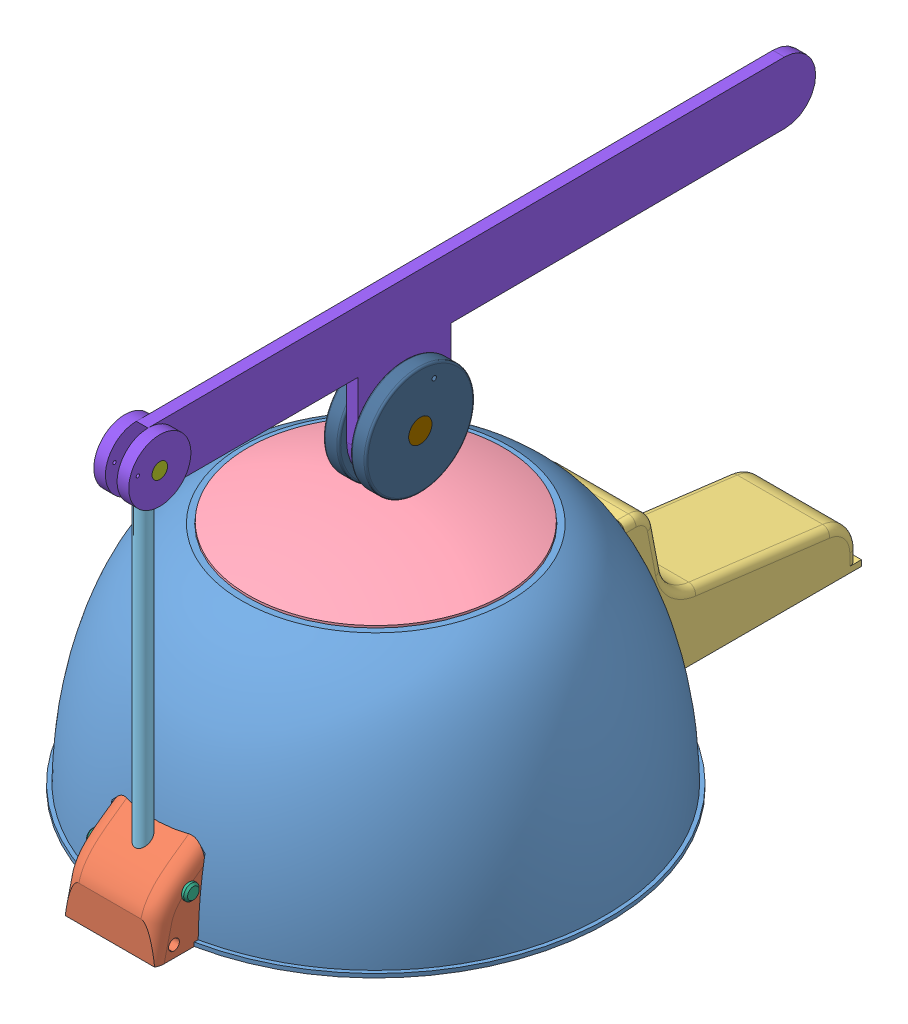
SolidWorks assembly 51  Coupe de l'assemblage, configuration Défaut. Lengths in mm.
Overall size (120 112.85 181.55).
12 component instances, 10 part files, 20 mates.
Components (placement in the parent):
- 1  Coupelle extérieure-1: 1  Coupelle extérieure [Défaut] at (42.4148 -15.5563 120.5) size (120 60 121.39)
- 2  Fixation arrière-1: 2  Fixation arrière [Défaut] at (-29.5852 -15.5563 177) x (0 0 -1) z (1 0 0) size (14.24 23.41 24.92)
- 3  Fixation avant-1: 3  Fixation avant [Défaut] at (-30.4444 -15.7632 69.5) x (0 0 -1) z (1 0 0) size (61 39.79 26)
- 4  Piston-1: 4  Piston [Défaut] at (-17.5852 33.9447 120.5) x (-0.981005 0 0.193982) z (-0.193982 0 -0.981005) size (65.8 16 65.8)
- 51  Assemblage-1: 51  Assemblage [Défaut] at (122.4148 13.8625 229.7525) x (0 0 1) z (-1 0 0) size (4 94 26)
  - 5  Tige de rappel-1: 5  Tige de rappel [Défaut] at (-51.2525 -16.4187 140) size (4 90 4)
  - 6  Tige transversale Bas-1: 6  Tige transversale Bas [Défaut] at (-49.2525 -16.4187 127) size (4 4 26)
  - 8 Tige transversale Haut-1: 8 Tige transversale Haut [Défaut] at (-49.2525 73.5813 144.6486) x (0 0 -1) z (1 0 0) size (9 4 4)
- 7  Levier-1: 7  Levier [Défaut] at (-19.2338 80.3433 -3.5369) x (0 0.004888 -0.999988) z (1 0 0) size (180 44 9)
- 10  Axe de roulettes-1: 10  Axe de roulettes [Défaut] at (-23.2338 63.7666 114.3835) size (11 6 6)
- 9  Roulettes-1: 9  Roulettes [Défaut] at (-12.2338 63.7666 114.3835) x (0 -0.542815 0.839852) z (-1 0 0) size (28 28 4)
- 9  Roulettes-2: 9  Roulettes [Défaut] at (-19.2338 63.7666 114.3835) x (0 0 1) z (-1 0 0) size (28 28 4)
Mates (geometry in assembly coordinates):
- Coïncidente1: coincident anti-aligned: plane of 1  Coupelle extérieure-1 through (42.4148 -15.5563 176.5) normal (0 0 1); plane of 2  Fixation arrière-1 through (-5.5852 6.4437 176.5) normal (0 0 -1)
- Coïncidente2: coincident aligned: plane of 1  Coupelle extérieure-1 through (-75.5852 -15.5563 120.5) normal (0 -1 0); plane of 2  Fixation arrière-1 through (-5.5852 -15.5563 176.5) normal (0 -1 0)
- Coïncidente3: coincident anti-aligned: plane of 1  Coupelle extérieure-1 through (-5.5852 -16.5563 176.5) normal (-1 0 0); plane of 2  Fixation arrière-1 through (-5.5852 0.9524 183.9253) normal (1 0 0)
- Coïncidente4: coincident anti-aligned: plane of 1  Coupelle extérieure-1 through (42.4148 -15.5563 69.5) normal (0 0 -1); plane of 3  Fixation avant-1 through (-4.4444 24.2368 69.5) normal (0 0 1)
- Coïncidente5: coincident anti-aligned: plane of 1  Coupelle extérieure-1 through (-4.4444 23.4437 69.5) normal (-1 0 0); plane of 3  Fixation avant-1 through (-4.4444 11.0983 49.7454) normal (1 0 0)
- Coïncidente6: coincident aligned: plane of 1  Coupelle extérieure-1 through (-75.5852 -15.5563 120.5) normal (0 -1 0); plane of 3  Fixation avant-1 through (-4.4444 -15.5563 8.5) normal (0 -1 0)
- Parallèle1: parallel anti-aligned: line of 2  Fixation arrière-1 through (-6.0734 -15.5563 189) axis (-1 0 0); cylinder of 51  Assemblage-1/6  Tige transversale Bas-1 through (-30.5852 -2.5563 180.5) axis (1 0 0) radius 2
- Coaxiale3: concentric aligned: cylinder of 2  Fixation arrière-1 through (-29.9836 -2.5563 180.5) axis (1 0 0) radius 2; cylinder of 51  Assemblage-1/6  Tige transversale Bas-1 through (-30.5852 -2.5563 180.5) axis (1 0 0) radius 2
- Coaxiale1: concentric anti-aligned: cylinder of 1  Coupelle extérieure-1 through (-17.5852 10.4437 120.5) axis (0 1 0) radius 33; cylinder of 4  Piston-1 through (-17.5852 33.9447 120.5) axis (0 -1 0) radius 32.9
- Coaxiale4: concentric anti-aligned: cylinder of 51  Assemblage-1/8 Tige transversale Haut-1 through (-13.2338 87.4437 180.5) axis (-1 0 0) radius 2; cylinder of 7  Levier-1 through (-22.2338 87.4437 180.5) axis (1 0 0) radius 2
- Coïncidente7: coincident aligned: plane of 51  Assemblage-1/8 Tige transversale Haut-1 through (-13.2338 87.4437 180.5) normal (1 0 0); plane of 7  Levier-1 through (-13.2338 87.4437 180.5) normal (1 0 0)
- Coaxiale2: concentric aligned: cylinder of 2  Fixation arrière-1 through (-17.5852 6.8422 180.5) axis (0 -1 0) radius 2; cylinder of 51  Assemblage-1/5  Tige de rappel-1 through (-17.5852 -2.5563 180.5) axis (0 -1 0) radius 2
- Coaxiale5: concentric aligned: cylinder of 7  Levier-1 through (-16.2338 63.7666 114.3835) axis (-1 0 0) radius 3; cylinder of 10  Axe de roulettes-1 through (-12.2338 63.7666 114.3835) axis (-1 0 0) radius 3
- Distance5: distance = 4 mm aligned: plane of 10  Axe de roulettes-1 through (-12.2338 63.7666 114.3835) normal (1 0 0); plane of 7  Levier-1 through (-16.2338 63.7666 114.3835) normal (1 0 0)
- Coaxiale6: concentric anti-aligned: cylinder of 10  Axe de roulettes-1 through (-12.2338 63.7666 114.3835) axis (-1 0 0) radius 3; cylinder of 9  Roulettes-1 through (-16.2338 63.7666 114.3835) axis (1 0 0) radius 3
- Coïncidente14: coincident aligned: plane of 10  Axe de roulettes-1 through (-12.2338 63.7666 114.3835) normal (1 0 0); plane of 9  Roulettes-1 through (-12.2338 63.7666 114.3835) normal (1 0 0)
- Coaxiale7: concentric anti-aligned: cylinder of 10  Axe de roulettes-1 through (-12.2338 63.7666 114.3835) axis (-1 0 0) radius 3; cylinder of 9  Roulettes-2 through (-23.2338 63.7666 114.3835) axis (1 0 0) radius 3
- Coïncidente15: coincident aligned: plane of 10  Axe de roulettes-1 through (-23.2338 63.7666 114.3835) normal (-1 0 0); plane of 9  Roulettes-2 through (-23.2338 63.7666 114.3835) normal (-1 0 0)
- AngleLimite3: limit planar angle = 1.570796 rad aligned: plane of 7  Levier-1 through (-16.2338 79.7078 126.4615) normal (0 -1 0); plane of 2  Fixation arrière-1 through (-5.5852 -15.5563 189) normal (0 0 1); plane of 1  Coupelle extérieure-1 through (-5.5852 -16.5563 176.5) normal (-1 0 0)
- Tangent5: tangent: face of 4  Piston-1; cylinder of 9  Roulettes-1 through (-16.2338 63.7666 114.3835) axis (1 0 0) radius 14
